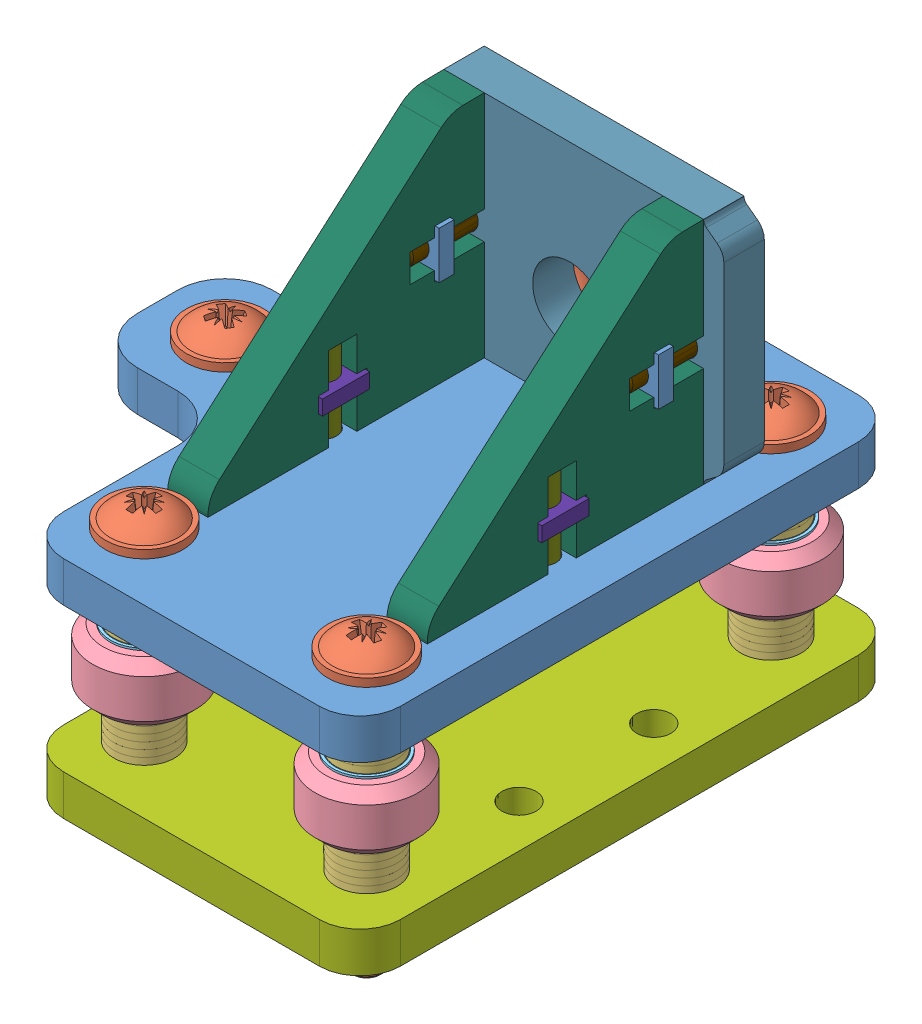
SolidWorks assembly carriage_y_r, configuration По умолчанию. Lengths in mm.
Overall size (94.17 94.07 98.19).
132 component instances, 19 part files, 163 mates.
Components (placement in the parent):
- bottom_y_r-4: bottom_y_r [По умолчанию] at origin size (70 6 80)
- DIN967din-1: DIN967din [М5х40] at (-17 9.55 -30) x (0 -1 0) z (0 0 1) size (43.47 34 34.42)
- DIN967din-2: DIN967din [М5х40] at (-17 9.55 30) x (0 -1 0) z (0 0 1) size (43.47 34 34.42)
- DIN967din-3: DIN967din [М5х40] at (16 9.55 -30) x (0 -1 0) z (0 0 1) size (43.47 34 34.42)
- DIN967din-4: DIN967din [М5х40] at (16 9.55 30) x (0 -1 0) z (0.973575 0 0.228367) size (43.47 34 34.42)
- din433_m5-1: din433_m5 [По умолчанию] at (16 0 30) x (1 0 0) z (0 -1 0) size (9 9 1)
- din433_m5-2: din433_m5 [По умолчанию] at (16 -2 30) x (-0.882011 0 -0.471229) z (0 1 0) size (9 9 1)
- din433_m5-3: din433_m5 [По умолчанию] at (16 -3 30) x (-0.882011 0 -0.471229) z (0 1 0) size (9 9 1)
- din433_m5-4: din433_m5 [По умолчанию] at (16 -4 30) x (-0.882011 0 -0.471229) z (0 1 0) size (9 9 1)
- din433_m5-5: din433_m5 [По умолчанию] at (16 -5 30) x (-0.986157 0 -0.165812) z (0 1 0) size (9 9 1)
- din433_m5-6: din433_m5 [По умолчанию] at (16 -3 -30) x (-0.882011 0 -0.471229) z (0 1 0) size (9 9 1)
- din433_m5-7: din433_m5 [По умолчанию] at (16 -2 -30) x (-0.882011 0 -0.471229) z (0 1 0) size (9 9 1)
- din433_m5-8: din433_m5 [По умолчанию] at (16 -1 -30) x (-0.706556 0 -0.707657) z (0 1 0) size (9 9 1)
- din433_m5-9: din433_m5 [По умолчанию] at (16 -4 -30) x (-0.882011 0 -0.471229) z (0 1 0) size (9 9 1)
- din433_m5-10: din433_m5 [По умолчанию] at (16 -5 -30) x (0.996128 0 0.087912) z (0 -1 0) size (9 9 1)
- din433_m5-11: din433_m5 [По умолчанию] at (16 -5 -30) x (-0.882011 0 -0.471229) z (0 1 0) size (9 9 1)
- din433_m5-12: din433_m5 [По умолчанию] at (-17 -3 30) x (-0.955012 0 -0.296566) z (0 1 0) size (9 9 1)
- din433_m5-13: din433_m5 [По умолчанию] at (-17 -4 30) x (-0.955012 0 -0.296566) z (0 1 0) size (9 9 1)
- din433_m5-14: din433_m5 [По умолчанию] at (-17 -5 30) x (-0.827257 0 -0.561823) z (0 1 0) size (9 9 1)
- din433_m5-15: din433_m5 [По умолчанию] at (-17 -2 30) x (-0.955012 0 -0.296566) z (0 1 0) size (9 9 1)
- din433_m5-16: din433_m5 [По умолчанию] at (-17 0 30) x (0.982082 0 -0.188455) z (0 -1 0) size (9 9 1)
- din433_m5-17: din433_m5 [По умолчанию] at (-17 -2 -30) x (-0.996489 0 -0.083718) z (0 1 0) size (9 9 1)
- din433_m5-18: din433_m5 [По умолчанию] at (-17 -3 -30) x (-0.996489 0 -0.083718) z (0 1 0) size (9 9 1)
- din433_m5-19: din433_m5 [По умолчанию] at (-17 -4 -30) x (-0.928921 0 -0.370279) z (0 1 0) size (9 9 1)
- din433_m5-20: din433_m5 [По умолчанию] at (-17 -1 -30) x (-0.996489 0 -0.083718) z (0 1 0) size (9 9 1)
- din433_m5-28: din433_m5 [По умолчанию] at (-17 -5 -30) x (0.980186 0 0.198081) z (0 -1 0) size (9 9 1)
- din433_m5-29: din433_m5 [По умолчанию] at (-17 -4 -30) x (0.980186 0 0.198081) z (0 -1 0) size (9 9 1)
- din433_m5-27: din433_m5 [По умолчанию] at (16 -5 30) x (0.91627 0 0.40056) z (0 -1 0) size (9 9 1)
- din433_m5-21: din433_m5 [По умолчанию] at (-17 -6 30) x (-0.552382 0 -0.833591) z (0 1 0) size (9 9 1)
- Delrin Mini V Wheel Kit-1: Delrin Mini V Wheel Kit [По умолчанию] at (-17 -10.7 30) x (0 1 0) z (0 0 1) size (9.4 15.23 15.23)
  - Delrin Mini V Wheel-1: Delrin Mini V Wheel [Default] at origin size (8.8 15.23 15.23)
  - Mini Ball Bearing 105zz 5x10x4-1: Mini Ball Bearing 105zz 5x10x4 [Default] at (2.6 0 0) size (4.2 10 10)
  - Mini Ball Bearing 105zz 5x10x4-2: Mini Ball Bearing 105zz 5x10x4 [Default] at (-2.6 0 0) size (4.2 10 10)
  - Mini V Wheel Precision Shim-2: Mini V Wheel Precision Shim [По умолчанию] at (-0.5 0 0) size (1 8 8)
- din433_m5-30: din433_m5 [По умолчанию] at (-17 -19.4 30) x (0.999952 0 0.009811) z (0 -1 0) size (9 9 1)
- din433_m5-31: din433_m5 [По умолчанию] at (-17 -20.4 30) x (0.999952 0 0.009811) z (0 -1 0) size (9 9 1)
- din433_m5-32: din433_m5 [По умолчанию] at (-17 -16.4 30) x (-0.994411 0 0.105575) z (0 1 0) size (9 9 1)
- din433_m5-33: din433_m5 [По умолчанию] at (-17 -19.4 30) x (-0.982057 0 -0.188585) z (0 1 0) size (9 9 1)
- din433_m5-34: din433_m5 [По умолчанию] at (-17 -18.4 30) x (-0.994411 0 0.105575) z (0 1 0) size (9 9 1)
- din433_m5-35: din433_m5 [По умолчанию] at (-17 -17.4 30) x (-0.994411 0 0.105575) z (0 1 0) size (9 9 1)
- Delrin Mini V Wheel Kit-2: Delrin Mini V Wheel Kit [По умолчанию] at (-17 -10.7 -30) x (0 -1 0) z (0.990454 0 -0.137844) size (9.4 15.23 15.23)
  - Delrin Mini V Wheel-1: Delrin Mini V Wheel [Default] at origin size (8.8 15.23 15.23)
  - Mini Ball Bearing 105zz 5x10x4-1: Mini Ball Bearing 105zz 5x10x4 [Default] at (2.6 0 0) size (4.2 10 10)
  - Mini Ball Bearing 105zz 5x10x4-2: Mini Ball Bearing 105zz 5x10x4 [Default] at (-2.6 0 0) size (4.2 10 10)
  - Mini V Wheel Precision Shim-2: Mini V Wheel Precision Shim [По умолчанию] at (-0.5 0 0) size (1 8 8)
- din433_m5-42: din433_m5 [По умолчанию] at (-17 -20.4 -30) x (0.983884 0 -0.17881) z (0 -1 0) size (9 9 1)
- din433_m5-43: din433_m5 [По умолчанию] at (-17 -16.4 -30) x (-0.956697 0 0.291085) z (0 1 0) size (9 9 1)
- din433_m5-44: din433_m5 [По умолчанию] at (-17 -19.4 -30) x (-1 0 -0.000132) z (0 1 0) size (9 9 1)
- din433_m5-45: din433_m5 [По умолчанию] at (-17 -18.4 -30) x (-0.956697 0 0.291085) z (0 1 0) size (9 9 1)
- din433_m5-46: din433_m5 [По умолчанию] at (-17 -17.4 -30) x (-0.956697 0 0.291085) z (0 1 0) size (9 9 1)
- din433_m5-47: din433_m5 [По умолчанию] at (-17 -19.4 -30) x (0.983884 0 -0.17881) z (0 -1 0) size (9 9 1)
- Delrin Mini V Wheel Kit-3: Delrin Mini V Wheel Kit [По умолчанию] at (16 -10.7 -30) x (0 1 0) z (0 0 1) size (9.4 15.23 15.23)
  - Delrin Mini V Wheel-1: Delrin Mini V Wheel [Default] at origin size (8.8 15.23 15.23)
  - Mini Ball Bearing 105zz 5x10x4-1: Mini Ball Bearing 105zz 5x10x4 [Default] at (2.6 0 0) size (4.2 10 10)
  - Mini Ball Bearing 105zz 5x10x4-2: Mini Ball Bearing 105zz 5x10x4 [Default] at (-2.6 0 0) size (4.2 10 10)
  - Mini V Wheel Precision Shim-2: Mini V Wheel Precision Shim [По умолчанию] at (-0.5 0 0) size (1 8 8)
- Delrin Mini V Wheel Kit-4: Delrin Mini V Wheel Kit [По умолчанию] at (16 -10.7 30) x (0 -1 0) z (-0.546944 0 0.837169) size (9.4 15.23 15.23)
  - Delrin Mini V Wheel-1: Delrin Mini V Wheel [Default] at origin size (8.8 15.23 15.23)
  - Mini Ball Bearing 105zz 5x10x4-1: Mini Ball Bearing 105zz 5x10x4 [Default] at (2.6 0 0) size (4.2 10 10)
  - Mini Ball Bearing 105zz 5x10x4-2: Mini Ball Bearing 105zz 5x10x4 [Default] at (-2.6 0 0) size (4.2 10 10)
  - Mini V Wheel Precision Shim-2: Mini V Wheel Precision Shim [По умолчанию] at (-0.5 0 0) size (1 8 8)
- din433_m5-54: din433_m5 [По умолчанию] at (16 -16.4 30) x (-0.124351 0 0.992238) z (0 1 0) size (9 9 1)
- din433_m5-55: din433_m5 [По умолчанию] at (16 -19.4 30) x (-0.982107 0 0.188325) z (0 1 0) size (9 9 1)
- din433_m5-56: din433_m5 [По умолчанию] at (16 -18.4 30) x (-0.884699 0 0.466164) z (0 1 0) size (9 9 1)
- din433_m5-57: din433_m5 [По умолчанию] at (16 -17.4 30) x (-0.884699 0 0.466164) z (0 1 0) size (9 9 1)
- din433_m5-58: din433_m5 [По умолчанию] at (16 -19.4 30) x (0.932557 0 -0.361024) z (0 -1 0) size (9 9 1)
- din433_m5-59: din433_m5 [По умолчанию] at (16 -20.4 30) x (0.932557 0 -0.361024) z (0 -1 0) size (9 9 1)
- din433_m5-132: din433_m5 [По умолчанию] at (16 -18.4 -30) x (-0.884699 0 0.466164) z (0 1 0) size (9 9 1)
- din433_m5-133: din433_m5 [По умолчанию] at (16 -20.4 -30) x (0.932557 0 -0.361024) z (0 -1 0) size (9 9 1)
- din433_m5-134: din433_m5 [По умолчанию] at (16 -19.4 -30) x (0.932557 0 -0.361024) z (0 -1 0) size (9 9 1)
- din433_m5-135: din433_m5 [По умолчанию] at (16 -17.4 -30) x (-0.884699 0 0.466164) z (0 1 0) size (9 9 1)
- din433_m5-136: din433_m5 [По умолчанию] at (16 -19.4 -30) x (-0.982107 0 0.188325) z (0 1 0) size (9 9 1)
- din433_m5-137: din433_m5 [По умолчанию] at (16 -16.4 -30) x (0.998156 0 0.060708) z (0 1 0) size (9 9 1)
- top_y_r-5: top_y_r [По умолчанию] at (0 -27.4 0) size (70 6 80)
- DIN 985-1: DIN 985 [Verzle DIN 985 - M5] at (-17 -27.4 -30) x (0 1 0) z (1 0 0) size (5 9.24 8)
- DIN 985-2: DIN 985 [Verzle DIN 985 - M5] at (-17 -27.4 30) x (0 1 0) z (1 0 0) size (5 9.24 8)
- DIN 985-3: DIN 985 [Verzle DIN 985 - M5] at (16 -27.4 -30) x (0 1 0) z (1 0 0) size (5 9.24 8)
- DIN 985-4: DIN 985 [Verzle DIN 985 - M5] at (16 -27.4 30) x (0 1 0) z (1 0 0) size (5 9.24 8)
- DIN967din-5: DIN967din [М5х60] at (-35 9.55 0) x (0 -1 0) z (-0.837169 0 -0.546944) size (63.47 34 34.42)
- din433_m5-138: din433_m5 [По умолчанию] at (-35 -27.4 0) x (-0.837241 0 -0.546833) z (0 -1 0) size (9 9 1)
- din433_m5-139: din433_m5 [По умолчанию] at (-35 -37.9 0) x (1 0 0.000132) z (0 1 0) size (9 9 1)
- din433_m5-140: din433_m5 [По умолчанию] at (-35 -28.4 0) x (-0.837241 0 -0.546833) z (0 -1 0) size (9 9 1)
- din433_m5-141: din433_m5 [По умолчанию] at (-35 -29.4 0) x (-0.837241 0 -0.546833) z (0 -1 0) size (9 9 1)
- GT2 Timing Idler Pulley, Configurable-2: GT2 Timing Idler Pulley, Configurable [20T W6 B5 With T] at (-35 -34.65 0) x (-0.902064 0 0.431602) z (0.431602 0 0.902064) size (25.08 8.5 25.08)
  - Body, GT2 Timing Idler Pulley, Configurable-1: Body, GT2 Timing Idler Pulley, Configurable [20T W6 B5 With T] x (-0.574695 0 -0.818368) z (0.818368 0 -0.574695) size (18 8.5 18)
  - Bearing Subassy, GT2 Timing Idler Pulley, Configurable-1: Bearing Subassy, GT2 Timing Idler Pulley, Configurable [5 mm Bore] at (0 2.75 0) x (0.574695 0 0.818368) z (-0.818368 0 0.574695) size (9 3 9)
    - Bearing Outer Ring, GT2 Timing Idler Pulley, Configurable-1: Bearing Outer Ring, GT2 Timing Idler Pulley, Configurable [5 mm Bore] at origin size (9 3 9)
    - Bearing Inner Ring, GT2 Timing Idler Pulley, Configurable-1: Bearing Inner Ring, GT2 Timing Idler Pulley, Configurable [5 mm Bore] x (0.926062 0 -0.377371) z (0.377371 0 0.926062) size (6 3 6)
    - Bearing Seal, GT2 Timing Idler Pulley, Configurable-1: Bearing Seal, GT2 Timing Idler Pulley, Configurable [5 mm Bore] at (0 1.25 0) size (8 0.5 8)
    - Bearing Seal, GT2 Timing Idler Pulley, Configurable-2: Bearing Seal, GT2 Timing Idler Pulley, Configurable [5 mm Bore] at (0 -1.25 0) x (1 0 0) z (0 0 -1) size (8 0.5 8)
    - Bearing Ball, GT2 Timing Idler Pulley, Configurable-1: Bearing Ball, GT2 Timing Idler Pulley, Configurable [1.4 mm] at (-2.4745 0 -2.4753) x (-0.715461 0 0.698652) z (-0.698652 0 -0.715461) size (1.4 1.4 1.4)
    - Bearing Ball, GT2 Timing Idler Pulley, Configurable-2: Bearing Ball, GT2 Timing Idler Pulley, Configurable [1.4 mm] at (-0.9053 0 -3.3809) x (-0.968934 0 0.24732) z (-0.24732 0 -0.968934) size (1.4 1.4 1.4)
    - Bearing Ball, GT2 Timing Idler Pulley, Configurable-3: Bearing Ball, GT2 Timing Idler Pulley, Configurable [1.4 mm] at (0.9064 0 -3.3806) x (-0.962781 0 -0.270282) z (0.270282 0 -0.962781) size (1.4 1.4 1.4)
    - Bearing Ball, GT2 Timing Idler Pulley, Configurable-4: Bearing Ball, GT2 Timing Idler Pulley, Configurable [1.4 mm] at (2.4753 0 -2.4745) x (-0.698652 0 -0.715461) z (0.715461 0 -0.698652) size (1.4 1.4 1.4)
    - Bearing Ball, GT2 Timing Idler Pulley, Configurable-5: Bearing Ball, GT2 Timing Idler Pulley, Configurable [1.4 mm] at (3.3809 0 -0.9053) x (-0.24732 0 -0.968934) z (0.968934 0 -0.24732) size (1.4 1.4 1.4)
    - Bearing Ball, GT2 Timing Idler Pulley, Configurable-6: Bearing Ball, GT2 Timing Idler Pulley, Configurable [1.4 mm] at (3.3806 0 0.9064) x (0.270282 0 -0.962781) z (0.962781 0 0.270282) size (1.4 1.4 1.4)
    - Bearing Ball, GT2 Timing Idler Pulley, Configurable-7: Bearing Ball, GT2 Timing Idler Pulley, Configurable [1.4 mm] at (2.4745 0 2.4753) x (0.715461 0 -0.698652) z (0.698652 0 0.715461) size (1.4 1.4 1.4)
    - Bearing Ball, GT2 Timing Idler Pulley, Configurable-8: Bearing Ball, GT2 Timing Idler Pulley, Configurable [1.4 mm] at (0.9053 0 3.3809) x (0.968934 0 -0.24732) z (0.24732 0 0.968934) size (1.4 1.4 1.4)
    - Bearing Ball, GT2 Timing Idler Pulley, Configurable-9: Bearing Ball, GT2 Timing Idler Pulley, Configurable [1.4 mm] at (-0.9064 0 3.3806) x (0.962781 0 0.270282) z (-0.270282 0 0.962781) size (1.4 1.4 1.4)
    - Bearing Ball, GT2 Timing Idler Pulley, Configurable-10: Bearing Ball, GT2 Timing Idler Pulley, Configurable [1.4 mm] at (-2.4753 0 2.4745) x (0.698652 0 0.715461) z (-0.715461 0 0.698652) size (1.4 1.4 1.4)
    - Bearing Ball, GT2 Timing Idler Pulley, Configurable-11: Bearing Ball, GT2 Timing Idler Pulley, Configurable [1.4 mm] at (-3.3809 0 0.9053) x (0.24732 0 0.968934) z (-0.968934 0 0.24732) size (1.4 1.4 1.4)
    - Bearing Ball, GT2 Timing Idler Pulley, Configurable-12: Bearing Ball, GT2 Timing Idler Pulley, Configurable [1.4 mm] at (-3.3806 0 -0.9064) x (-0.270282 0 0.962781) z (-0.962781 0 -0.270282) size (1.4 1.4 1.4)
  - Bearing Subassy, GT2 Timing Idler Pulley, Configurable-2: Bearing Subassy, GT2 Timing Idler Pulley, Configurable [5 mm Bore] at (0 -2.75 0) x (0.574695 0 0.818368) z (0.818368 0 -0.574695) size (9 3 9)
    - Bearing Outer Ring, GT2 Timing Idler Pulley, Configurable-1: Bearing Outer Ring, GT2 Timing Idler Pulley, Configurable [5 mm Bore] at origin size (9 3 9)
    - Bearing Inner Ring, GT2 Timing Idler Pulley, Configurable-1: Bearing Inner Ring, GT2 Timing Idler Pulley, Configurable [5 mm Bore] x (0.926062 0 -0.377371) z (0.377371 0 0.926062) size (6 3 6)
    - Bearing Seal, GT2 Timing Idler Pulley, Configurable-1: Bearing Seal, GT2 Timing Idler Pulley, Configurable [5 mm Bore] at (0 1.25 0) size (8 0.5 8)
    - Bearing Seal, GT2 Timing Idler Pulley, Configurable-2: Bearing Seal, GT2 Timing Idler Pulley, Configurable [5 mm Bore] at (0 -1.25 0) x (1 0 0) z (0 0 -1) size (8 0.5 8)
    - Bearing Ball, GT2 Timing Idler Pulley, Configurable-1: Bearing Ball, GT2 Timing Idler Pulley, Configurable [1.4 mm] at (-2.4745 0 -2.4753) x (-0.715461 0 0.698652) z (-0.698652 0 -0.715461) size (1.4 1.4 1.4)
    - Bearing Ball, GT2 Timing Idler Pulley, Configurable-2: Bearing Ball, GT2 Timing Idler Pulley, Configurable [1.4 mm] at (-0.9053 0 -3.3809) x (-0.968934 0 0.24732) z (-0.24732 0 -0.968934) size (1.4 1.4 1.4)
    - Bearing Ball, GT2 Timing Idler Pulley, Configurable-3: Bearing Ball, GT2 Timing Idler Pulley, Configurable [1.4 mm] at (0.9064 0 -3.3806) x (-0.962781 0 -0.270282) z (0.270282 0 -0.962781) size (1.4 1.4 1.4)
    - Bearing Ball, GT2 Timing Idler Pulley, Configurable-4: Bearing Ball, GT2 Timing Idler Pulley, Configurable [1.4 mm] at (2.4753 0 -2.4745) x (-0.698652 0 -0.715461) z (0.715461 0 -0.698652) size (1.4 1.4 1.4)
    - Bearing Ball, GT2 Timing Idler Pulley, Configurable-5: Bearing Ball, GT2 Timing Idler Pulley, Configurable [1.4 mm] at (3.3809 0 -0.9053) x (-0.24732 0 -0.968934) z (0.968934 0 -0.24732) size (1.4 1.4 1.4)
    - Bearing Ball, GT2 Timing Idler Pulley, Configurable-6: Bearing Ball, GT2 Timing Idler Pulley, Configurable [1.4 mm] at (3.3806 0 0.9064) x (0.270282 0 -0.962781) z (0.962781 0 0.270282) size (1.4 1.4 1.4)
    - Bearing Ball, GT2 Timing Idler Pulley, Configurable-7: Bearing Ball, GT2 Timing Idler Pulley, Configurable [1.4 mm] at (2.4745 0 2.4753) x (0.715461 0 -0.698652) z (0.698652 0 0.715461) size (1.4 1.4 1.4)
    - Bearing Ball, GT2 Timing Idler Pulley, Configurable-8: Bearing Ball, GT2 Timing Idler Pulley, Configurable [1.4 mm] at (0.9053 0 3.3809) x (0.968934 0 -0.24732) z (0.24732 0 0.968934) size (1.4 1.4 1.4)
    - Bearing Ball, GT2 Timing Idler Pulley, Configurable-9: Bearing Ball, GT2 Timing Idler Pulley, Configurable [1.4 mm] at (-0.9064 0 3.3806) x (0.962781 0 0.270282) z (-0.270282 0 0.962781) size (1.4 1.4 1.4)
    - Bearing Ball, GT2 Timing Idler Pulley, Configurable-10: Bearing Ball, GT2 Timing Idler Pulley, Configurable [1.4 mm] at (-2.4753 0 2.4745) x (0.698652 0 0.715461) z (-0.715461 0 0.698652) size (1.4 1.4 1.4)
    - Bearing Ball, GT2 Timing Idler Pulley, Configurable-11: Bearing Ball, GT2 Timing Idler Pulley, Configurable [1.4 mm] at (-3.3809 0 0.9053) x (0.24732 0 0.968934) z (-0.968934 0 0.24732) size (1.4 1.4 1.4)
    - Bearing Ball, GT2 Timing Idler Pulley, Configurable-12: Bearing Ball, GT2 Timing Idler Pulley, Configurable [1.4 mm] at (-3.3806 0 -0.9064) x (-0.270282 0 0.962781) z (-0.962781 0 -0.270282) size (1.4 1.4 1.4)
- DIN 985-6: DIN 985 [Verzle DIN 985 - M5] at (-35 -39.9 0) x (0 1 0) z (0.999816 0 -0.019163) size (5 9.24 8)
- din433_m5-142: din433_m5 [По умолчанию] at (-35 -38.9 0) x (-0.837241 0 -0.546833) z (0 -1 0) size (9 9 1)
- carriage_y_console-1: carriage_y_console [По умолчанию] at (-4.2954 -0.1715 -23) size (44.55 34.07 6)
- carriage_y_console_rectangel-1: carriage_y_console_rectangel [По умолчанию] at (13 -0.0784 -23) x (0 0 1) z (-1 0 0) size (47 40.07 6)
- carriage_y_console_rectangel-2: carriage_y_console_rectangel [По умолчанию] at (-19.55 -0.0784 -23) x (0 0 1) z (-1 0 0) size (47 40.07 6)
- DIN 7991-1: DIN 7991 [ISO 7991 M04 x  16] at (16 0 4) x (0 1 0) z (1 0 0) size (18.3 40 22.08)
- din 562 m4din-3: din 562 m4din [По умолчанию] at (16 11 4) x (0 0 1) z (0 1 0) size (7 7 2.2)
- DIN 7991-2: DIN 7991 [ISO 7991 M04 x  16] at (-16.55 0 4) x (0 1 0) z (-1 0 0) size (18.3 40 22.08)
- din 562 m4din-4: din 562 m4din [По умолчанию] at (-16.55 11 4) x (0 0 -1) z (0 1 0) size (7 7 2.2)
- DIN967-9: DIN967 [M4х16] at (-16.55 23 -26.05) x (0 0 1) z (-1 0 0) size (18.96 34 34.42)
- din 562 m4-6: din 562 m4 [По умолчанию] at (-16.5482 22.9998 -12) x (0 1 0) z (0 0 1) size (7 7 2.2)
- DIN967-10: DIN967 [M4х16] at (16 23 -26.05) x (0 0 1) z (1 0 0) size (18.96 34 34.42)
- din 562 m4-7: din 562 m4 [По умолчанию] at (15.9982 23.0002 -12) x (0 -1 0) z (0 0 1) size (7 7 2.2)
Mates (geometry in assembly coordinates):
- Концентричный11: concentric anti-aligned: cylinder of bottom_y_r-4 through (-17 6 -30) axis (0 -1 0) radius 2.55; cylinder of DIN967din-1 through (-17 15.9 -30) axis (0 1 0) radius 5.75
- Совпадение11: coincident anti-aligned: plane of bottom_y_r-4 through (19 6 -34) normal (0 1 0); plane of DIN967din-1 through (-14.5 6 -30) normal (0 -1 0)
- Концентричный21: concentric anti-aligned: cylinder of bottom_y_r-4 through (-17 6 30) axis (0 -1 0) radius 2.55; cylinder of DIN967din-2 through (-17 15.9 30) axis (0 1 0) radius 5.75
- Совпадение21: coincident anti-aligned: plane of bottom_y_r-4 through (19 6 -34) normal (0 1 0); plane of DIN967din-2 through (-14.5 6 30) normal (0 -1 0)
- Концентричный31: concentric anti-aligned: cylinder of DIN967din-3 through (16 15.9 -30) axis (0 1 0) radius 5.75; circle of carriage_axis_y_plywood_left-1
- Совпадение31: coincident anti-aligned: plane of bottom_y_r-4 through (19 6 -34) normal (0 1 0); plane of DIN967din-3 through (18.5 6 -30) normal (0 -1 0)
- Совпадение41: coincident anti-aligned: plane of bottom_y_r-4 through (19 6 -34) normal (0 1 0); plane of DIN967din-4 through (16.5709 6 27.5661) normal (0 -1 0)
- Концентричный5: concentric anti-aligned: cylinder of bottom_y_r-4 through (16 6 30) axis (0 -1 0) radius 2.55; cylinder of DIN967din-4 through (16 15.9 30) axis (0 1 0) radius 2.5
- Совпадение5: coincident anti-aligned: plane of bottom_y_r-4 through (19 0 -34) normal (0 -1 0); plane of din433_m5-1 through (16 0 30) normal (0 1 0)
- Концентричный6: concentric anti-aligned: cylinder of DIN967din-4 through (16 15.9 30) axis (0 1 0) radius 2.5; circle of din433_m5-1
- Концентричный7: concentric aligned: cylinder of DIN967din-4 through (16 15.9 30) axis (0 1 0) radius 2.5; circle of din433_m5-2
- Совпадение7: coincident anti-aligned: plane of din433_m5-1 through (16 -1 30) normal (0 -1 0); plane of din433_m5-2 through (16 -1 30) normal (0 1 0)
- Совпадение10: coincident anti-aligned: plane of din433_m5-3 through (16 -3 30) normal (0 -1 0); plane of din433_m5-4 through (16 -3 30) normal (0 1 0)
- Совпадение11: coincident aligned: circle of din433_m5-3; circle of din433_m5-4
- Совпадение12: coincident anti-aligned: plane of din433_m5-4 through (16 -4 30) normal (0 -1 0); plane of din433_m5-5 through (16 -4 30) normal (0 1 0)
- Совпадение13: coincident aligned: circle of din433_m5-4; circle of din433_m5-5
- Совпадение14: coincident anti-aligned: plane of din433_m5-2 through (16 -2 30) normal (0 -1 0); plane of din433_m5-3 through (16 -2 30) normal (0 1 0)
- Совпадение15: coincident aligned: circle of din433_m5-2; circle of din433_m5-3
- Совпадение16: coincident anti-aligned: plane of bottom_y_r-4 through (19 0 -34) normal (0 -1 0); plane of din433_m5-8 through (16 0 -30) normal (0 1 0)
- Концентричный8: concentric aligned: cylinder of DIN967din-3 through (16 15.9 -30) axis (0 1 0) radius 2.5; circle of din433_m5-8
- Совпадение17: coincident anti-aligned: plane of din433_m5-7 through (16 -1 -30) normal (0 1 0); plane of din433_m5-8 through (16 -1 -30) normal (0 -1 0)
- Совпадение18: coincident aligned: circle of din433_m5-7; circle of din433_m5-8
- Совпадение19: coincident anti-aligned: plane of din433_m5-6 through (16 -2 -30) normal (0 1 0); plane of din433_m5-7 through (16 -2 -30) normal (0 -1 0)
- Концентричный9: concentric aligned: cylinder of DIN967din-3 through (16 15.9 -30) axis (0 1 0) radius 2.5; circle of din433_m5-6
- Совпадение20: coincident anti-aligned: plane of din433_m5-6 through (16 -3 -30) normal (0 -1 0); plane of din433_m5-9 through (16 -3 -30) normal (0 1 0)
- Концентричный10: concentric aligned: cylinder of DIN967din-3 through (16 15.9 -30) axis (0 1 0) radius 2.5; circle of din433_m5-9
- Совпадение22: coincident anti-aligned: plane of din433_m5-9 through (16 -4 -30) normal (0 -1 0); plane of din433_m5-11 through (16 -4 -30) normal (0 1 0)
- Концентричный11: concentric aligned: cylinder of DIN967din-3 through (16 15.9 -30) axis (0 1 0) radius 2.5; circle of din433_m5-11
- Совпадение23: coincident anti-aligned: plane of din433_m5-10 through (16 -5 -30) normal (0 1 0); plane of din433_m5-11 through (16 -5 -30) normal (0 -1 0)
- Концентричный13: concentric anti-aligned: cylinder of DIN967din-3 through (16 15.9 -30) axis (0 1 0) radius 2.5; circle of din433_m5-10
- Совпадение24: coincident anti-aligned: plane of din433_m5-15 through (-17 -1 30) normal (0 1 0); plane of din433_m5-16 through (-17 -1 30) normal (0 -1 0)
- Совпадение25: coincident anti-aligned: plane of din433_m5-12 through (-17 -3 30) normal (0 -1 0); plane of din433_m5-13 through (-17 -3 30) normal (0 1 0)
- Совпадение26: coincident aligned: circle of din433_m5-12; circle of din433_m5-13
- Совпадение27: coincident anti-aligned: plane of din433_m5-13 through (-17 -4 30) normal (0 -1 0); plane of din433_m5-14 through (-17 -4 30) normal (0 1 0)
- Совпадение28: coincident aligned: circle of din433_m5-13; circle of din433_m5-14
- Совпадение29: coincident anti-aligned: plane of din433_m5-12 through (-17 -2 30) normal (0 1 0); plane of din433_m5-15 through (-17 -2 30) normal (0 -1 0)
- Совпадение30: coincident aligned: circle of din433_m5-12; circle of din433_m5-15
- Совпадение33: coincident anti-aligned: plane of din433_m5-17 through (-17 -2 -30) normal (0 -1 0); plane of din433_m5-18 through (-17 -2 -30) normal (0 1 0)
- Совпадение34: coincident aligned: circle of din433_m5-17; circle of din433_m5-18
- Совпадение35: coincident anti-aligned: plane of din433_m5-18 through (-17 -3 -30) normal (0 -1 0); plane of din433_m5-19 through (-17 -3 -30) normal (0 1 0)
- Совпадение36: coincident aligned: circle of din433_m5-18; circle of din433_m5-19
- Совпадение37: coincident anti-aligned: plane of din433_m5-17 through (-17 -1 -30) normal (0 1 0); plane of din433_m5-20 through (-17 -1 -30) normal (0 -1 0)
- Совпадение38: coincident aligned: circle of din433_m5-17; circle of din433_m5-20
- Концентричный15: concentric aligned: cylinder of DIN967din-2 through (-17 15.9 30) axis (0 1 0) radius 2.5; circle of din433_m5-14
- Концентричный16: concentric anti-aligned: cylinder of DIN967din-2 through (-17 15.9 30) axis (0 1 0) radius 2.5; circle of din433_m5-16
- Совпадение54: coincident anti-aligned: plane of din433_m5-14 through (-17 -5 30) normal (0 -1 0); plane of din433_m5-21 through (-17 -5 30) normal (0 1 0)
- Концентричный17: concentric aligned: cylinder of DIN967din-2 through (-17 15.9 30) axis (0 1 0) radius 2.5; circle of din433_m5-21
- Совпадение55: coincident anti-aligned: plane of din433_m5-5 through (16 -5 30) normal (0 -1 0); plane of din433_m5-27 through (16 -5 30) normal (0 1 0)
- Концентричный18: concentric anti-aligned: cylinder of DIN967din-4 through (16 15.9 30) axis (0 1 0) radius 2.5; circle of din433_m5-27
- Концентричный19: concentric aligned: cylinder of DIN967din-1 through (-17 15.9 -30) axis (0 1 0) radius 2.5; circle of din433_m5-20
- Совпадение56: coincident anti-aligned: plane of din433_m5-19 through (-17 -4 -30) normal (0 -1 0); plane of din433_m5-29 through (-17 -4 -30) normal (0 1 0)
- Концентричный20: concentric anti-aligned: cylinder of DIN967din-1 through (-17 15.9 -30) axis (0 1 0) radius 2.5; circle of din433_m5-29
- Совпадение57: coincident anti-aligned: plane of din433_m5-28 through (-17 -5 -30) normal (0 1 0); plane of din433_m5-29 through (-17 -5 -30) normal (0 -1 0)
- Концентричный21: concentric anti-aligned: cylinder of DIN967din-1 through (-17 15.9 -30) axis (0 1 0) radius 2.5; circle of din433_m5-28
- Совпадение58: coincident anti-aligned: plane of bottom_y_r-4 through (19 0 -34) normal (0 -1 0); plane of din433_m5-20 through (-17 0 -30) normal (0 1 0)
- Совпадение59: coincident anti-aligned: plane of din433_m5-21 through (-17 -6 30) normal (0 -1 0); plane of Delrin Mini V Wheel Kit-1/Mini Ball Bearing 105zz 5x10x4-1 through (-19.5 -6 30) normal (0 1 0)
- Совпадение60: coincident aligned: cylinder of DIN967din-2 through (-17 15.9 30) axis (0 1 0) radius 2.5; circle of Delrin Mini V Wheel Kit-1/Mini Ball Bearing 105zz 5x10x4-2
- Совпадение61: coincident anti-aligned: plane of din433_m5-34 through (-17 -17.4 30) normal (0 1 0); plane of din433_m5-35 through (-17 -17.4 30) normal (0 -1 0)
- Совпадение62: coincident aligned: circle of din433_m5-34; circle of din433_m5-35
- Совпадение63: coincident anti-aligned: plane of din433_m5-33 through (-17 -18.4 30) normal (0 1 0); plane of din433_m5-34 through (-17 -18.4 30) normal (0 -1 0)
- Совпадение64: coincident aligned: circle of din433_m5-33; circle of din433_m5-34
- Совпадение65: coincident anti-aligned: plane of din433_m5-32 through (-17 -16.4 30) normal (0 -1 0); plane of din433_m5-35 through (-17 -16.4 30) normal (0 1 0)
- Совпадение67: coincident anti-aligned: plane of din433_m5-30 through (-17 -19.4 30) normal (0 1 0); plane of din433_m5-33 through (-17 -19.4 30) normal (0 -1 0)
- Совпадение68: coincident anti-aligned: plane of din433_m5-30 through (-17 -20.4 30) normal (0 -1 0); plane of din433_m5-31 through (-17 -20.4 30) normal (0 1 0)
- Совпадение80: coincident anti-aligned: plane of Delrin Mini V Wheel Kit-1/Mini Ball Bearing 105zz 5x10x4-2 through (-19.5 -15.4 30) normal (0 -1 0); plane of din433_m5-32 through (-17 -15.4 30) normal (0 1 0)
- Концентричный22: concentric aligned: cylinder of DIN967din-2 through (-17 15.9 30) axis (0 1 0) radius 2.5; circle of din433_m5-32
- Концентричный23: concentric aligned: cylinder of DIN967din-2 through (-17 15.9 30) axis (0 1 0) radius 2.5; circle of din433_m5-35
- Концентричный24: concentric anti-aligned: cylinder of DIN967din-2 through (-17 15.9 30) axis (0 1 0) radius 2.5; circle of din433_m5-30
- Концентричный25: concentric aligned: cylinder of DIN967din-2 through (-17 15.9 30) axis (0 1 0) radius 2.5; cylinder of din433_m5-31 through (-17 -21.4 30) axis (0 1 0) radius 4.5
- Совпадение81: coincident anti-aligned: plane of din433_m5-28 through (-17 -6 -30) normal (0 -1 0); plane of Delrin Mini V Wheel Kit-2/Mini Ball Bearing 105zz 5x10x4-2 through (-17.3446 -6 -32.4761) normal (0 1 0)
- Совпадение82: coincident anti-aligned: cylinder of DIN967din-1 through (-17 15.9 -30) axis (0 1 0) radius 2.5; circle of Delrin Mini V Wheel Kit-2/Mini Ball Bearing 105zz 5x10x4-1
- Совпадение83: coincident anti-aligned: plane of din433_m5-45 through (-17 -17.4 -30) normal (0 1 0); plane of din433_m5-46 through (-17 -17.4 -30) normal (0 -1 0)
- Совпадение84: coincident aligned: circle of din433_m5-45; circle of din433_m5-46
- Совпадение85: coincident anti-aligned: plane of din433_m5-44 through (-17 -18.4 -30) normal (0 1 0); plane of din433_m5-45 through (-17 -18.4 -30) normal (0 -1 0)
- Совпадение86: coincident aligned: circle of din433_m5-44; circle of din433_m5-45
- Совпадение87: coincident anti-aligned: plane of din433_m5-43 through (-17 -16.4 -30) normal (0 -1 0); plane of din433_m5-46 through (-17 -16.4 -30) normal (0 1 0)
- Совпадение88: coincident anti-aligned: plane of din433_m5-44 through (-17 -19.4 -30) normal (0 -1 0); plane of din433_m5-47 through (-17 -19.4 -30) normal (0 1 0)
- Совпадение89: coincident anti-aligned: plane of din433_m5-42 through (-17 -20.4 -30) normal (0 1 0); plane of din433_m5-47 through (-17 -20.4 -30) normal (0 -1 0)
- Совпадение99: coincident anti-aligned: plane of bottom_y_r-4 through (19 0 -34) normal (0 -1 0); plane of din433_m5-16 through (-17 0 30) normal (0 1 0)
- Совпадение100: coincident anti-aligned: plane of Delrin Mini V Wheel Kit-2/Mini Ball Bearing 105zz 5x10x4-1 through (-17.3446 -15.4 -32.4761) normal (0 -1 0); plane of din433_m5-43 through (-17 -15.4 -30) normal (0 1 0)
- Концентричный26: concentric anti-aligned: circle of din433_m5-42; circle of din433_m5-43
- Концентричный27: concentric anti-aligned: circle of din433_m5-43; circle of din433_m5-47
- Концентричный28: concentric anti-aligned: circle of din433_m5-42; circle of din433_m5-44
- Концентричный29: concentric aligned: circle of Delrin Mini V Wheel Kit-2/Mini Ball Bearing 105zz 5x10x4-1; cylinder of din433_m5-43 through (-17 -15.4 -30) axis (0 -1 0) radius 4.5
- Совпадение104: coincident anti-aligned: plane of din433_m5-10 through (16 -6 -30) normal (0 -1 0); plane of Delrin Mini V Wheel Kit-3/Mini Ball Bearing 105zz 5x10x4-1 through (13.5 -6 -30) normal (0 1 0)
- Совпадение105: coincident aligned: cylinder of DIN967din-3 through (16 15.9 -30) axis (0 1 0) radius 2.5; circle of Delrin Mini V Wheel Kit-3/Mini Ball Bearing 105zz 5x10x4-2
- Совпадение106: coincident anti-aligned: plane of din433_m5-27 through (16 -6 30) normal (0 -1 0); plane of Delrin Mini V Wheel Kit-4/Mini Ball Bearing 105zz 5x10x4-2 through (18.0929 -6 31.3674) normal (0 1 0)
- Концентричный30: concentric anti-aligned: cylinder of DIN967din-4 through (16 15.9 30) axis (0 1 0) radius 2.5; cylinder of Delrin Mini V Wheel Kit-4/Mini Ball Bearing 105zz 5x10x4-1 through (16 -13.3 30) axis (0 -1 0) radius 2.5
- Совпадение107: coincident anti-aligned: plane of din433_m5-56 through (16 -17.4 30) normal (0 1 0); plane of din433_m5-57 through (16 -17.4 30) normal (0 -1 0)
- Совпадение108: coincident aligned: circle of din433_m5-56; circle of din433_m5-57
- Совпадение109: coincident anti-aligned: plane of din433_m5-55 through (16 -18.4 30) normal (0 1 0); plane of din433_m5-56 through (16 -18.4 30) normal (0 -1 0)
- Совпадение110: coincident aligned: circle of din433_m5-55; circle of din433_m5-56
- Совпадение111: coincident anti-aligned: plane of din433_m5-54 through (16 -16.4 30) normal (0 -1 0); plane of din433_m5-57 through (16 -16.4 30) normal (0 1 0)
- Совпадение112: coincident anti-aligned: plane of din433_m5-55 through (16 -19.4 30) normal (0 -1 0); plane of din433_m5-58 through (16 -19.4 30) normal (0 1 0)
- Совпадение113: coincident anti-aligned: plane of din433_m5-58 through (16 -20.4 30) normal (0 -1 0); plane of din433_m5-59 through (16 -20.4 30) normal (0 1 0)
- Концентричный31: concentric anti-aligned: circle of din433_m5-54; circle of din433_m5-59
- Концентричный32: concentric anti-aligned: circle of din433_m5-54; circle of din433_m5-58
- Концентричный33: concentric anti-aligned: circle of din433_m5-55; circle of din433_m5-59
- Концентричный83: concentric anti-aligned: circle of din433_m5-133; circle of din433_m5-136
- Совпадение200: coincident anti-aligned: plane of din433_m5-132 through (16 -18.4 -30) normal (0 -1 0); plane of din433_m5-136 through (16 -18.4 -30) normal (0 1 0)
- Совпадение201: coincident aligned: circle of din433_m5-132; circle of din433_m5-135
- Совпадение202: coincident anti-aligned: plane of din433_m5-132 through (16 -17.4 -30) normal (0 1 0); plane of din433_m5-135 through (16 -17.4 -30) normal (0 -1 0)
- Концентричный84: concentric anti-aligned: circle of din433_m5-134; circle of din433_m5-137
- Совпадение203: coincident anti-aligned: plane of din433_m5-135 through (16 -16.4 -30) normal (0 1 0); plane of din433_m5-137 through (16 -16.4 -30) normal (0 -1 0)
- Концентричный85: concentric anti-aligned: circle of din433_m5-133; circle of din433_m5-137
- Совпадение204: coincident anti-aligned: plane of din433_m5-134 through (16 -19.4 -30) normal (0 1 0); plane of din433_m5-136 through (16 -19.4 -30) normal (0 -1 0)
- Совпадение205: coincident aligned: circle of din433_m5-132; circle of din433_m5-136
- Совпадение206: coincident anti-aligned: plane of din433_m5-133 through (16 -20.4 -30) normal (0 1 0); plane of din433_m5-134 through (16 -20.4 -30) normal (0 -1 0)
- Совпадение207: coincident anti-aligned: plane of Delrin Mini V Wheel Kit-3/Mini Ball Bearing 105zz 5x10x4-2 through (13.5 -15.4 -30) normal (0 -1 0); plane of din433_m5-137 through (16 -15.4 -30) normal (0 1 0)
- Концентричный86: concentric aligned: cylinder of DIN967din-3 through (16 15.9 -30) axis (0 1 0) radius 2.5; circle of din433_m5-137
- Совпадение208: coincident anti-aligned: plane of Delrin Mini V Wheel Kit-4/Mini Ball Bearing 105zz 5x10x4-1 through (18.0929 -15.4 31.3674) normal (0 -1 0); plane of din433_m5-54 through (16 -15.4 30) normal (0 1 0)
- Концентричный87: concentric aligned: cylinder of DIN967din-4 through (16 15.9 30) axis (0 1 0) radius 2.5; circle of din433_m5-54
- Концентричный88: concentric anti-aligned: cylinder of DIN967din-1 through (-17 15.9 -30) axis (0 1 0) radius 2.5; circle of carriage_axis_y_plywood_left-2
- Концентричный89: concentric anti-aligned: cylinder of DIN967din-2 through (-17 15.9 30) axis (0 1 0) radius 2.5; circle of carriage_axis_y_plywood_left-2
- Совпадение210: coincident anti-aligned: plane of din433_m5-42 through (-17 -21.4 -30) normal (0 -1 0); plane of top_y_r-5 through (19 -21.4 -34) normal (0 1 0)
- Совпадение211: coincident anti-aligned: plane of top_y_r-5 through (19 -27.4 -34) normal (0 -1 0); plane of DIN 985-1 through (-17 -27.4 -30) normal (0 1 0)
- Концентричный90: concentric anti-aligned: cylinder of DIN967din-1 through (-17 15.9 -30) axis (0 1 0) radius 2.5; cylinder of DIN 985-1 through (-17 -35.522 -30) axis (0 -1 0) radius 2.5
- Совпадение212: coincident anti-aligned: plane of top_y_r-5 through (19 -27.4 -34) normal (0 -1 0); plane of DIN 985-2 through (-17 -27.4 30) normal (0 1 0)
- Совпадение213: coincident anti-aligned: plane of top_y_r-5 through (19 -27.4 -34) normal (0 -1 0); plane of DIN 985-4 through (16 -27.4 30) normal (0 1 0)
- Совпадение214: coincident anti-aligned: plane of top_y_r-5 through (19 -27.4 -34) normal (0 -1 0); plane of DIN 985-3 through (16 -27.4 -30) normal (0 1 0)
- Концентричный91: concentric anti-aligned: cylinder of DIN967din-2 through (-17 15.9 30) axis (0 1 0) radius 2.5; cylinder of DIN 985-2 through (-17 -35.522 30) axis (0 -1 0) radius 2.5
- Концентричный92: concentric anti-aligned: cylinder of DIN967din-3 through (16 15.9 -30) axis (0 1 0) radius 2.5; cylinder of DIN 985-3 through (16 -35.522 -30) axis (0 -1 0) radius 2.5
- Концентричный93: concentric anti-aligned: cylinder of DIN967din-4 through (16 15.9 30) axis (0 1 0) radius 2.5; cylinder of DIN 985-4 through (16 -35.522 30) axis (0 -1 0) radius 2.5
- Совпадение215: coincident anti-aligned: plane of bottom_y_r-4 through (19 6 -34) normal (0 1 0); plane of DIN967din-5 through (-36.3674 6 2.0929) normal (0 -1 0)
- Концентричный94: concentric aligned: circle of bottom_y_r-4; cylinder of DIN967din-5 through (-35 15.9 0) axis (0 1 0) radius 2.5
- Концентричный95: concentric anti-aligned: cylinder of DIN967din-5 through (-35 15.9 0) axis (0 1 0) radius 2.5; circle of din433_m5-138
- Совпадение216: coincident anti-aligned: plane of top_y_r-5 through (19 -27.4 -34) normal (0 -1 0); plane of din433_m5-138 through (-35 -27.4 0) normal (0 1 0)
- Концентричный97: concentric anti-aligned: cylinder of DIN967din-5 through (-35 15.9 0) axis (0 1 0) radius 2.5; cylinder of din433_m5-139 through (-35 -36.9 0) axis (0 -1 0) radius 2.65
- Совпадение131: coincident aligned: circle of din433_m5-138; circle of din433_m5-140
- Совпадение136: coincident aligned: circle of din433_m5-140; circle of din433_m5-141
- Концентричный45: concentric anti-aligned: cylinder of DIN967din-5 through (-35 15.9 0) axis (0 1 0) radius 2.5; cylinder of GT2 Timing Idler Pulley, Configurable-2/Bearing Subassy, GT2 Timing Idler Pulley, Configurable-2/Bearing Inner Ring, GT2 Timing Idler Pulley, Configurable-1 through (-35 -30.4 0) axis (0 -1 0) radius 2.5
- Совпадение137: coincident anti-aligned: plane of din433_m5-141 through (-35 -30.4 0) normal (0 -1 0); plane of GT2 Timing Idler Pulley, Configurable-2/Bearing Subassy, GT2 Timing Idler Pulley, Configurable-2/Bearing Inner Ring, GT2 Timing Idler Pulley, Configurable-1 through (-35 -30.4 0) normal (0 1 0)
- Совпадение138: coincident anti-aligned: plane of GT2 Timing Idler Pulley, Configurable-2/Bearing Subassy, GT2 Timing Idler Pulley, Configurable-1/Bearing Seal, GT2 Timing Idler Pulley, Configurable-1 through (-35 -38.9 0) normal (0 -1 0); plane of din433_m5-142 through (-35 -38.9 0) normal (0 1 0)
- Концентричный98: concentric aligned: cylinder of DIN967din-5 through (-35 15.9 0) axis (0 1 0) radius 2.5; cylinder of din433_m5-142 through (-35 -39.9 0) axis (0 1 0) radius 2.65
- Концентричный47: concentric anti-aligned: cylinder of DIN967din-5 through (-35 15.9 0) axis (0 1 0) radius 2.5; cylinder of DIN 985-6 through (-35 -48.022 0) axis (0 -1 0) radius 2.5
- Совпадение140: coincident anti-aligned: plane of din433_m5-142 through (-35 -39.9 0) normal (0 -1 0); plane of DIN 985-6 through (-35 -39.9 0) normal (0 1 0)
- Расстояние1: distance = 17 mm aligned: plane of carriage_y_console-1 through (-4.2954 -0.1715 -23) normal (0 0 -1); plane of bottom_y_r-4 through (-19 6 -40) normal (0 0 -1)
- Совпадение219: coincident anti-aligned: plane of bottom_y_r-4 through (19 6 -34) normal (0 1 0); plane of carriage_y_console-1 through (-19.55 6 -17) normal (0 -1 0)
- Совпадение221: coincident anti-aligned: plane of bottom_y_r-4 through (19 6 -34) normal (0 1 0); plane of carriage_y_console_rectangel-1 through (19 6 24) normal (0 -1 0)
- Совпадение222: coincident anti-aligned: plane of carriage_y_console-1 through (-4.2954 -0.1715 -17) normal (0 0 1); plane of carriage_y_console_rectangel-1 through (19 40.0693 -17) normal (0 0 -1)
- Совпадение223: coincident aligned: plane of carriage_y_console-1 through (19 6 -17) normal (1 0 0); plane of carriage_y_console_rectangel-1 through (19 6.2312 19) normal (1 0 0)
- Совпадение224: coincident anti-aligned: plane of bottom_y_r-4 through (19 6 -34) normal (0 1 0); plane of carriage_y_console_rectangel-2 through (-13.55 6 24) normal (0 -1 0)
- Совпадение225: coincident anti-aligned: plane of carriage_y_console-1 through (-4.2954 -0.1715 -17) normal (0 0 1); plane of carriage_y_console_rectangel-2 through (-13.55 40.0693 -17) normal (0 0 -1)
- Совпадение226: coincident aligned: plane of carriage_y_console-1 through (-19.55 6 -17) normal (-1 0 0); plane of carriage_y_console_rectangel-2 through (-19.55 6.2312 19) normal (-1 0 0)
- Расстояние2: distance = 5.45 mm aligned: plane of carriage_y_console-1 through (-19.55 6 -17) normal (-1 0 0); plane of bottom_y_r-4 through (-25 6 -17) normal (-1 0 0)
- Совпадение2312: coincident anti-aligned: plane of carriage_y_console_rectangel-1 through (19 6.2312 19) normal (1 0 0); plane of DIN 7991-1 through (19 0 4) normal (-1 0 0)
- Совпадение2313: coincident aligned: plane of bottom_y_r-4 through (19 0 -34) normal (0 -1 0); plane of DIN 7991-1 through (16 0 4) normal (0 -1 0)
- Совпадение2314: coincident: line of carriage_y_console_rectangel-1 through (19 6 24) axis (0 1 0); plane of DIN 7991-1 through (16 0 24) normal (0 0 1)
- Совпадение2317: coincident: point of din 562 m4din-3; line of DIN 7991-1 through (16 18.3 4) axis (0 -1 0)
- Совпадение2318: coincident anti-aligned: plane of din 562 m4din-3 through (16 11 4) normal (0 -1 0); plane of carriage_y_console_rectangel-1 through (13 11 1.9) normal (0 1 0)
- Совпадение2319: coincident anti-aligned: plane of carriage_y_console_rectangel-2 through (-19.55 6.2312 19) normal (-1 0 0); plane of DIN 7991-2 through (-19.55 0 4) normal (1 0 0)
- Совпадение2320: coincident aligned: plane of bottom_y_r-4 through (19 0 -34) normal (0 -1 0); plane of DIN 7991-2 through (-16.55 0 4) normal (0 -1 0)
- Совпадение2321: coincident anti-aligned: plane of carriage_y_console_rectangel-2 through (-13.55 6 24) normal (0 0 1); plane of DIN 7991-2 through (-16.55 0 24) normal (0 0 -1)
- Совпадение2326: coincident: point of din 562 m4din-4; line of DIN 7991-2 through (-16.55 18.3 4) axis (0 -1 0)
- Совпадение2341: coincident anti-aligned: plane of carriage_y_console_rectangel-2 through (-19.55 6.2312 19) normal (-1 0 0); plane of DIN967-9 through (-19.55 23 -26.05) normal (1 0 0)
- Совпадение2342: coincident anti-aligned: plane of carriage_y_console-1 through (-4.2954 -0.1715 -23) normal (0 0 -1); plane of DIN967-9 through (-16.55 25 -23) normal (0 0 1)
- Совпадение2344: coincident: line of carriage_y_console-1 through (-19.55 6 -23) axis (1 0 0); plane of DIN967-9 through (-16.55 6 -26.05) normal (0 1 0)
- Концентричный106: concentric anti-aligned: cylinder of DIN967-9 through (-16.55 23 -32.4) axis (0 0 -1) radius 2; cylinder of din 562 m4-6 through (-16.55 23 -12) axis (0 0 1) radius 2
- Совпадение23451: coincident anti-aligned: plane of carriage_y_console-1 through (-4.2954 -0.1715 -23) normal (0 0 -1); plane of DIN967-10 through (16 21 -23) normal (0 0 1)
- Совпадение2346: coincident anti-aligned: plane of carriage_y_console-1 through (19 6 -17) normal (1 0 0); plane of DIN967-10 through (19 23 -26.05) normal (-1 0 0)
- Совпадение2347: coincident: line of carriage_y_console-1 through (-19.55 6 -23) axis (1 0 0); plane of DIN967-10 through (16 6 -26.05) normal (0 1 0)
- Концентричный108: concentric anti-aligned: cylinder of DIN967-10 through (16 23 -32.4) axis (0 0 -1) radius 2; cylinder of din 562 m4-7 through (16 23 -12) axis (0 0 1) radius 2
- Совпадение2348: coincident anti-aligned: plane of din 562 m4-7 through (15.9982 23.0002 -12) normal (0 0 -1); plane of carriage_y_console_rectangel-1 through (13 25.1 -12) normal (0 0 1)
